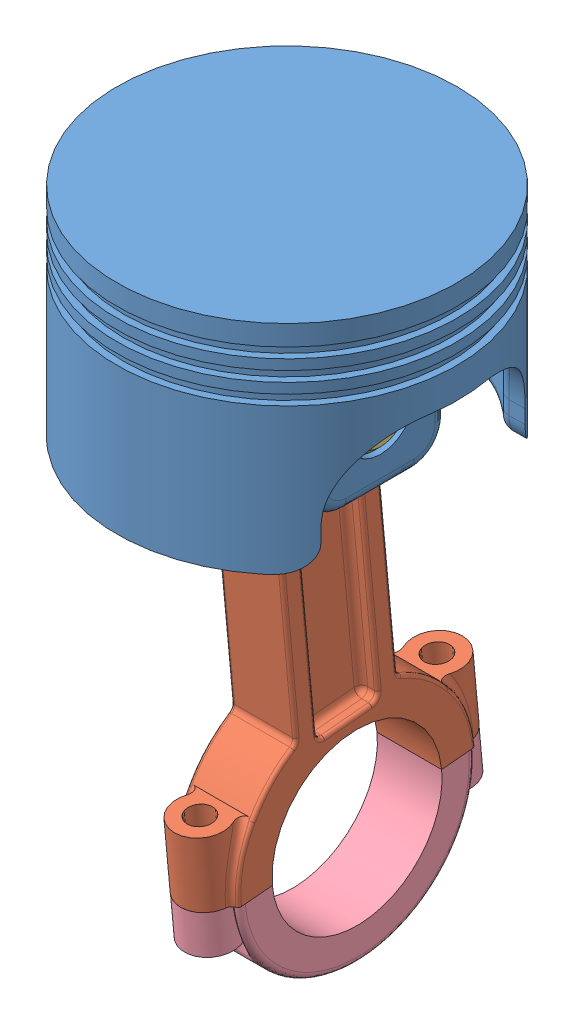
SolidWorks assembly Piston Completo, configuration Predeterminado. Lengths in mm.
Overall size (127 258.09 135.42).
4 component instances, 4 part files, 8 mates.
Components (placement in the parent):
- Piston Head-1: Piston Head [Predeterminado] at (19.3888 30.5642 127) size (127 82.5 127)
- Piston Holder-1: Piston Holder [Predeterminado] at (19.3888 -102.4101 119.9627) x (1 0 0) z (0 0.995726 0.092353) size (31.75 107.95 190.5)
- Piston Pin-1: Piston Pin [Predeterminado] at (19.3388 -26.5358 127) x (0 1 0) z (0 0 1) size (25.4 69.85 25.4)
- PistonAgarradera-2: PistonAgarradera [Predeterminado] at (19.3888 -178.2845 112.9254) x (-1 0 0) z (0 -0.092353 0.995726) size (26.54 45.22 107.95)
Mates (geometry in assembly coordinates):
- Concéntrica1: concentric aligned: cylinder of Piston Head-1 through (119.0138 -26.5358 127) axis (-1 0 0) radius 12.7; cylinder of Piston Holder-1 through (31.4538 -26.5358 127) axis (-1 0 0) radius 25.4
- Coincidente1: coincident anti-aligned: plane of Piston Head-1 through (35.2638 -51.9358 101.6) normal (-1 0 0); plane of Piston Holder-1 through (35.2638 -26.5358 127) normal (1 0 0)
- Concéntrica19: concentric aligned: cylinder of Piston Holder-1 through (19.3888 -150.1281 160.1777) axis (0 -0.995726 -0.092353) radius 4.76; cylinder of PistonAgarradera-2 through (19.3888 -197.5744 155.777) axis (0 -0.995726 -0.092353) radius 4.2164
- Coincidente8: coincident anti-aligned: plane of Piston Holder-1 through (31.4538 -178.2845 112.9254) normal (0 -0.995726 -0.092353); plane of PistonAgarradera-2 through (7.3238 -182.3896 157.1854) normal (0 0.995726 0.092353)
- Concéntrica24: concentric aligned: cylinder of Piston Holder-1 through (19.3888 -141.9179 71.6576) axis (0 -0.995726 -0.092353) radius 4.76; cylinder of PistonAgarradera-2 through (19.3888 -189.3642 67.257) axis (0 -0.995726 -0.092353) radius 4.2164
- Concéntrica25: concentric anti-aligned: cylinder of Piston Holder-1 through (31.4538 -26.5358 127) axis (-1 0 0) radius 25.4; cylinder of Piston Pin-1 through (-15.5862 -26.5358 127) axis (1 0 0) radius 12.7
- Coincidente9: coincident aligned: plane of Piston Head-1 through (54.2638 -51.9358 101.6) normal (1 0 0); plane of Piston Pin-1 through (54.2638 -26.5358 127) normal (1 0 0)
- Paralelo9: parallel: plane of assembly through (0 0 0) normal (0 1 0); plane of Piston Head-1 through (19.3888 30.5642 127) normal (0 1 0); plane of assembly
